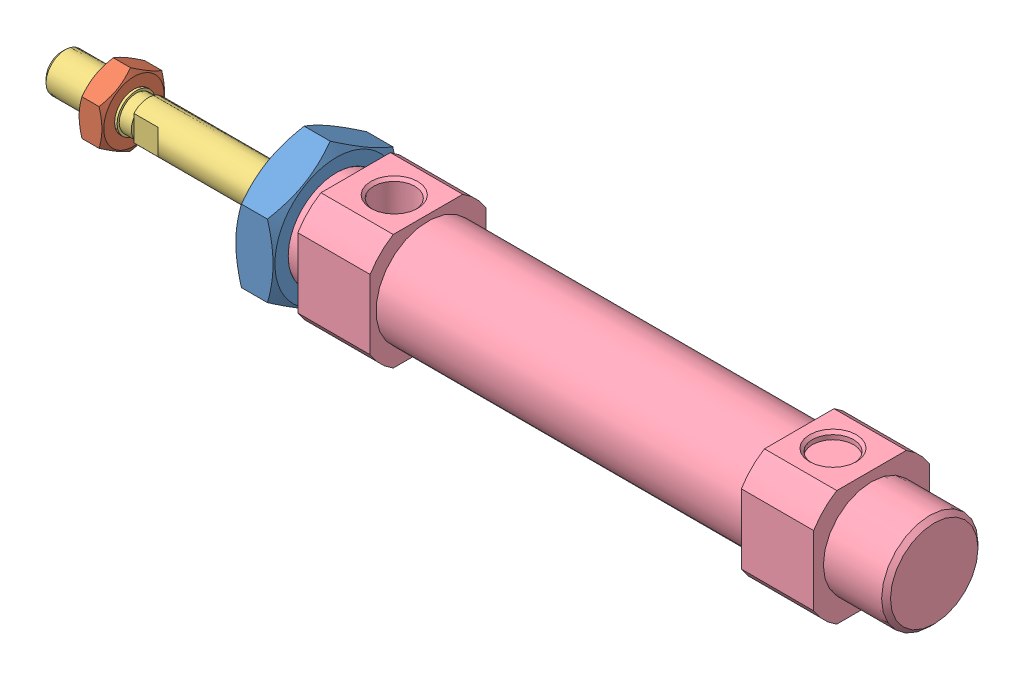
SolidWorks assembly CDM2F20-20TZ(0_1_0).stp, configuration Default. Lengths in mm.
Overall size (181 30.05 26.03).
5 component instances, 5 part files, 0 mates.
Components (placement in the parent):
- CM-F020B_Z(20_F_1_0)_FITTING.stp-1: CM-F020B_Z(20_F_1_0)_FITTING.stp [Default] at origin (suppressed, hidden)
- CM2_SN-020B(20).stp-1: CM2_SN-020B(20).stp [Default] at (-8 0 0) size (8 30.05 26.03)
- NT-02_CM2(20).stp-1: NT-02_CM2(20).stp [Default] at (-48.5 0 0) size (5 15.08 13.07)
- CM220-20TZ(0)_ROD.stp-1: CM220-20TZ(0)_ROD.stp [Default] at origin size (107 20 20)
- CDM2F20-20TZ(0)_BODY.stp-1: CDM2F20-20TZ(0)_BODY.stp [Default] at origin size (133 24 24)
